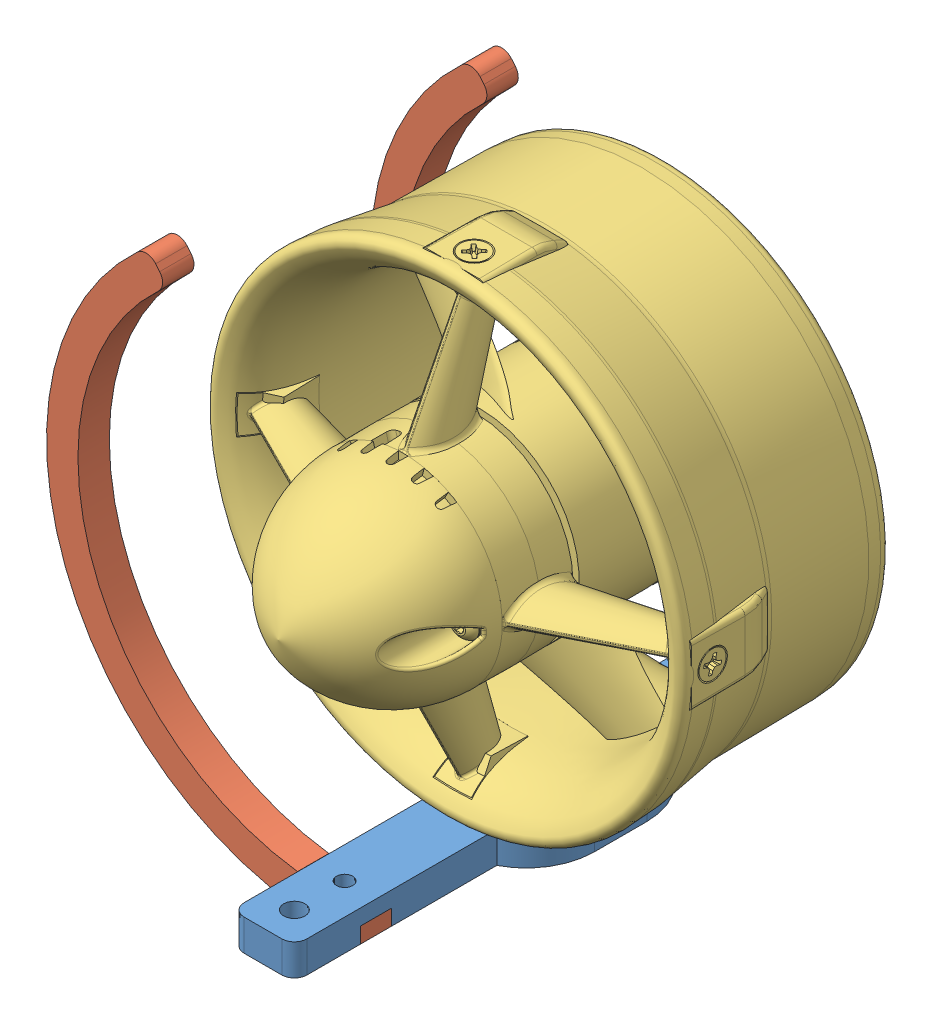
SolidWorks assembly thrusterAssem, configuration Default. Lengths in mm.
Overall size (105.5 103.7 103.88).
4 component instances, 3 part files, 9 mates.
Components (placement in the parent):
- basePlate-1: basePlate [Default] at (48.2602 47.9194 65.2477) size (44.79 6.35 98.66)
- guard-1: guard [Default] at (48.2602 104.7155 104.1263) size (63.5 99.49 6.35)
- guard-2: guard [Default] at (48.2602 104.7155 38.4815) size (63.5 99.49 6.35)
- T100-THRUSTER-R1-1: T100-THRUSTER-R1 [Default] at (48.2602 103.2694 65.2077) x (-1 0 0) z (0 0 1) size (96.71 97.51 100.86)
Mates (geometry in assembly coordinates):
- Coincident1: coincident anti-aligned: plane of basePlate-1 through (48.2602 51.0944 65.2477) normal (0 -1 0); plane of guard-1 through (48.2602 51.0944 110.4763) normal (0 1 0)
- Coincident2: coincident anti-aligned: plane of basePlate-1 through (48.2602 51.0944 104.1263) normal (0 0 1); plane of guard-1 through (48.2602 104.7155 104.1263) normal (0 0 -1)
- Coincident3: coincident aligned: plane of basePlate-1 through (54.6102 54.2694 82.8479) normal (1 0 0); plane of guard-1 through (54.6102 104.7155 110.4763) normal (1 0 0)
- Coincident4: coincident anti-aligned: plane of basePlate-1 through (48.2602 51.0944 65.2477) normal (0 -1 0); plane of guard-2 through (48.2602 51.0944 44.8315) normal (0 1 0)
- Coincident5: coincident aligned: plane of basePlate-1 through (54.6102 54.2694 47.6474) normal (1 0 0); plane of guard-2 through (54.6102 104.7155 44.8315) normal (1 0 0)
- Coincident6: coincident anti-aligned: plane of basePlate-1 through (48.2602 51.0944 38.4815) normal (0 0 1); plane of guard-2 through (48.2602 104.7155 38.4815) normal (0 0 -1)
- Coincident7: coincident anti-aligned: plane of basePlate-1 through (52.0702 54.2694 121.2713) normal (0 1 0); plane of T100-THRUSTER-R1-1 through (48.2602 54.2694 59.9559) normal (0 -1 0)
- Concentric2: concentric aligned: cylinder of basePlate-1 through (48.2602 50.6194 69.4559) axis (0 -1 0) radius 3.175; circle of T100-THRUSTER-R1-1
- Concentric3: concentric aligned: cylinder of basePlate-1 through (48.2602 50.6194 50.4559) axis (0 -1 0) radius 3.175; circle of T100-THRUSTER-R1-1
